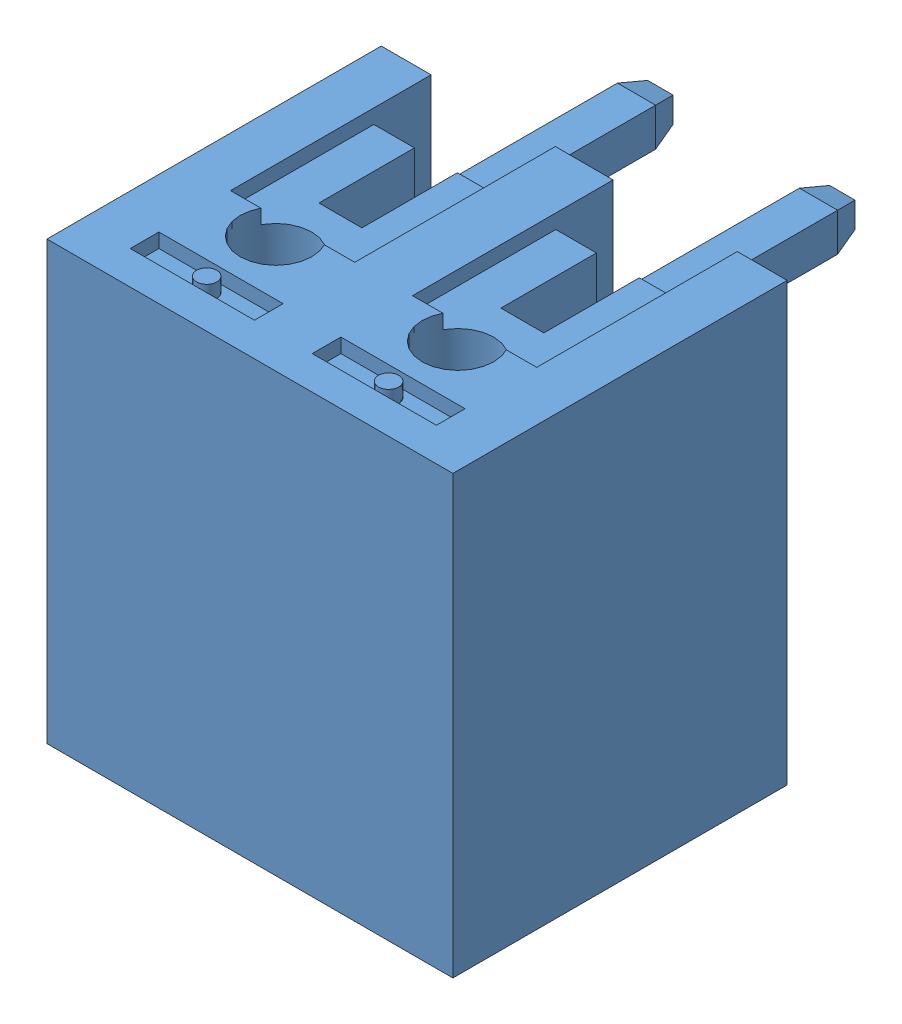
SolidWorks assembly KF2EDGR-3.81-2P, configuration Default. Lengths in mm.
Overall size (8.5 9.15 10.5).
3 component instances, 1 part files, 0 mates.
Components (placement in the parent):
- CN1-1: CN1 [Default] at (4.699 -2.413 1.6001) size (8.5 9.15 10.5)
  - CONN-TH_2P-P3.81_KF2EDGR-3.81-2P-1: CONN-TH_2P-P3.81_KF2EDGR-3.81-2P [Default] at origin size (8.5 9.15 10.5)
    - =_[0_1_1_5]-1: =_[0_1_1_5] [Default] at (-1.905 -0.35 0) size (8.5 9.15 10.5)
